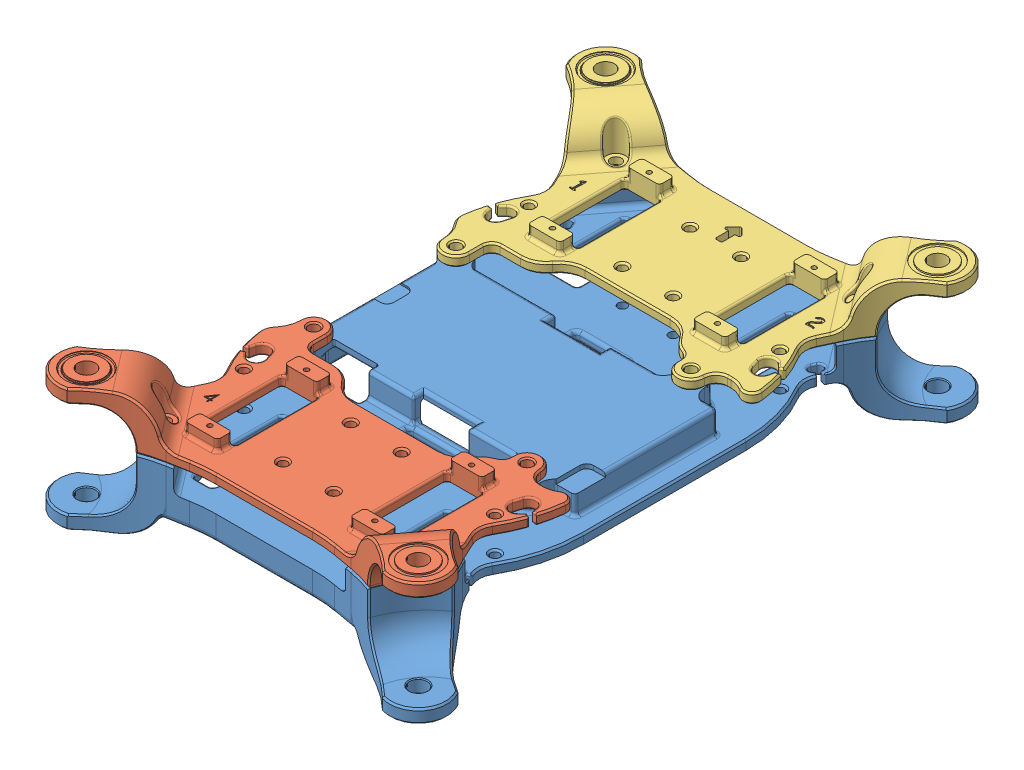
SolidWorks assembly chassis subassembly_new, configuration Default. Lengths in mm.
Overall size (114.75 36.11 174.01).
3 component instances, 3 part files, 4 mates.
Components (placement in the parent):
- SD-202 Chassis Bottom_new-1: SD-202 Chassis Bottom_new [Default] at (43.289 117.9377 146.0023) size (114.75 21.5 174.01)
- SD-201 Chassis Back_new-1: SD-201 Chassis Back_new [Default] at (43.289 118.0517 146.0023) size (114.75 14.53 68)
- SD-201 Chassis Front_new-1: SD-201 Chassis Front_new [Default] at (43.289 117.9377 146.0023) size (114.75 14.53 68)
Mates (geometry in assembly coordinates):
- Concentric1: concentric: circle of SD-202 Chassis Bottom_new-1; circle of SD-201 Chassis Front_new-1
- Concentric2: concentric: circle of SD-202 Chassis Bottom_new-1; circle of SD-201 Chassis Front_new-1
- Coincident1: coincident: plane of SD-202 Chassis Bottom_new-1 through (82.3059 121.4377 95.3529) normal (0 1 0); plane of SD-201 Chassis Front_new-1 through (82.3059 121.4377 95.3529) normal (0 -1 0)
- Concentric3: concentric: circle of SD-202 Chassis Bottom_new-1; circle of SD-201 Chassis Back_new-1
